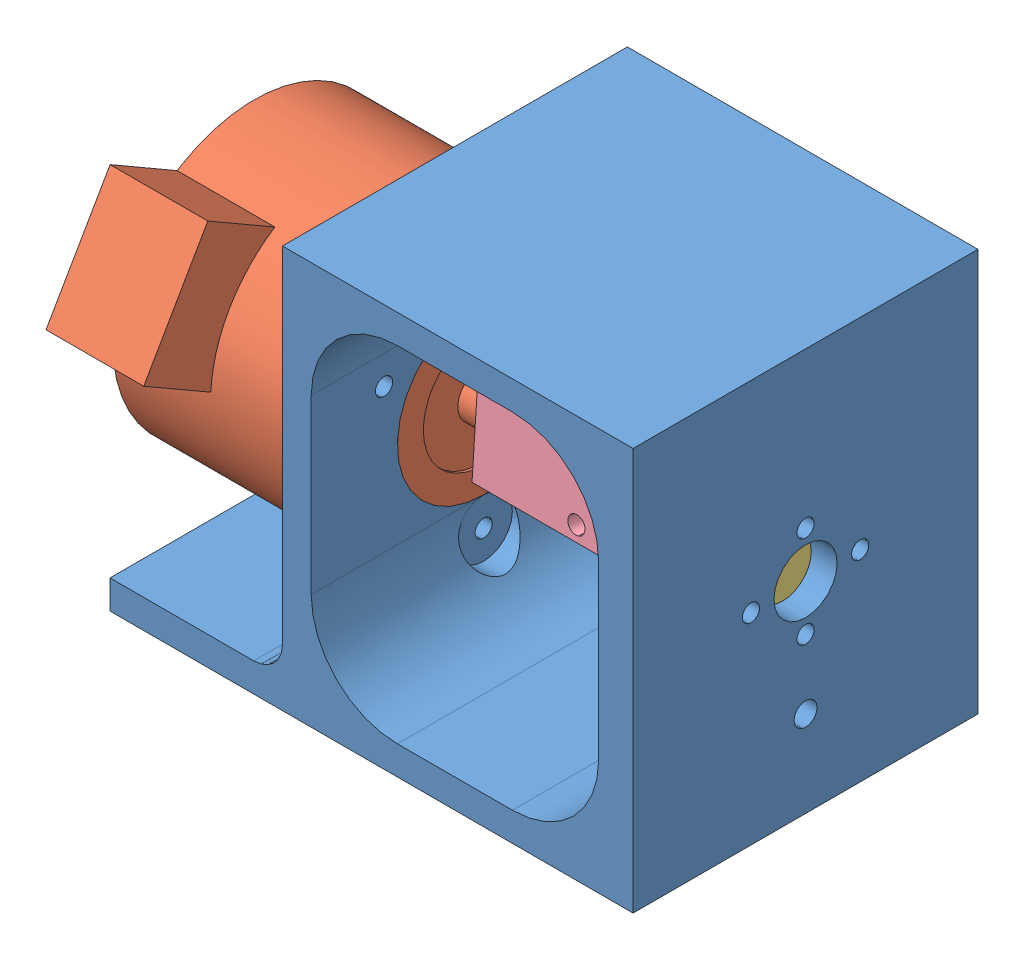
SolidWorks assembly AbsEnc_BLDC_testing, configuration Default. Lengths in mm.
Overall size (95.9 74 76.56).
4 component instances, 4 part files, 8 mates.
Components (placement in the parent):
- AbsEnc_mount-1: AbsEnc_mount [Default] at (-1.7883 43.8223 78.0183) size (91 70 60)
- Absolute Encoder-1: Absolute Encoder [Default] at (-13.601 60.1386 54.5641) x (0 -0.866025 0.5) z (0 0.5 0.866025) size (49.2 54.9 60)
- BLDC-1: BLDC [Default] at (83.2117 78.8223 108.0183) x (0 0 1) z (0 -1 0) size (28.4 32.5 28.4)
- shaft_adapter-1: shaft_adapter [Default] at (37.7117 78.8223 108.0183) x (1 0 0) z (0 -0.997765 0.06682) size (22 12 20)
Mates (geometry in assembly coordinates):
- Concentric1: concentric aligned: cylinder of AbsEnc_mount-1 through (33.2117 78.8223 108.0183) axis (-1 0 0) radius 15; cylinder of Absolute Encoder-1 through (33.2117 78.8223 108.0183) axis (-1 0 0) radius 15
- Concentric2: concentric anti-aligned: cylinder of AbsEnc_mount-1 through (33.2117 88.8223 125.3388) axis (-1 0 0) radius 1.5; cylinder of Absolute Encoder-1 through (20.2117 88.8223 125.3388) axis (1 0 0) radius 1
- Coincident1: coincident anti-aligned: plane of AbsEnc_mount-1 through (28.2117 43.8223 138.0183) normal (-1 0 0); plane of Absolute Encoder-1 through (28.2117 78.8223 108.0183) normal (1 0 0)
- Concentric3: concentric aligned: cylinder of AbsEnc_mount-1 through (89.2117 78.8223 108.0183) axis (-1 0 0) radius 5.5; cylinder of BLDC-1 through (85.2117 78.8223 108.0183) axis (-1 0 0) radius 5
- Concentric4: concentric anti-aligned: cylinder of AbsEnc_mount-1 through (89.2117 78.8223 117.5183) axis (-1 0 0) radius 1.5; cylinder of BLDC-1 through (83.2117 78.8223 117.5183) axis (1 0 0) radius 1.5
- Coincident3: coincident anti-aligned: plane of AbsEnc_mount-1 through (83.2117 43.8223 138.0183) normal (-1 0 0); plane of BLDC-1 through (83.2117 78.8223 108.0183) normal (1 0 0)
- Concentric5: concentric aligned: cylinder of BLDC-1 through (52.7117 78.8223 108.0183) axis (1 0 0) radius 2.5; cylinder of shaft_adapter-1 through (49.7117 78.8223 108.0183) axis (1 0 0) radius 2.5
- Distance1: distance = 5 mm anti-aligned: plane of shaft_adapter-1 through (37.7117 78.8223 108.0183) normal (-1 0 0); plane of Absolute Encoder-1 through (32.7117 78.8223 108.0183) normal (1 0 0)
